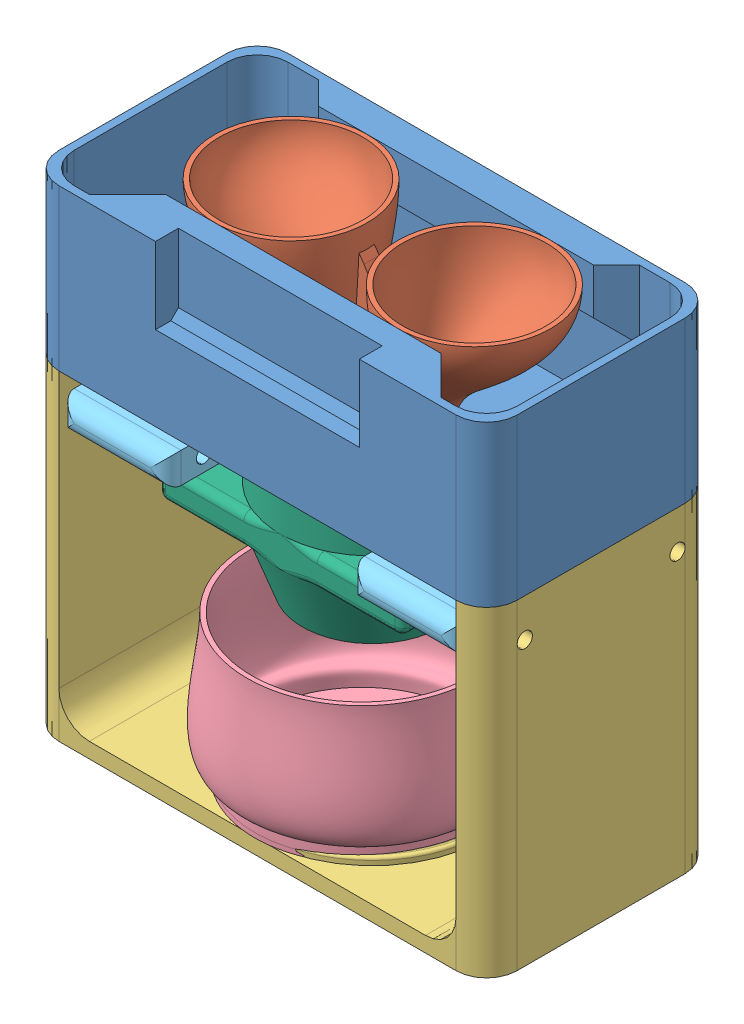
SolidWorks assembly sc_i_assembly, configuration Default. Lengths in mm.
Overall size (300 315.12 201.42).
6 component instances, 6 part files, 12 mates.
Components (placement in the parent):
- sc_i_body-1: sc_i_body [Default] at origin size (300 105 150)
- sc_i_bicontainer-2: sc_i_bicontainer [Default] at (92.0199 105 -80) x (-1 0 0) z (0 0 1) size (231.55 100.25 110.3)
- sc_i_base-1: sc_i_base [Default] at (0 -210 0) size (300 210 150)
- sc_i_pot-1: sc_i_pot [Default] at (148.9424 -197 -69.4018) size (200.61 98.32 201.42)
- sc_i_brewbase-1: sc_i_brewbase [Default] at (20 -35 0) size (260 20 150)
- sc_i_brewer-1: sc_i_brewer [Default] at (150 -35 -75) size (160 95 120)
Mates (geometry in assembly coordinates):
- Coincident7: coincident anti-aligned: plane of sc_i_body-1 through (0 5 0) normal (0 1 0); plane of sc_i_bicontainer-2 through (177.0199 5 -80) normal (0 -1 0)
- Coincident8: coincident anti-aligned: plane of sc_i_body-1 through (0 5 0) normal (0 1 0); plane of sc_i_bicontainer-2 through (127.0199 5 -80) normal (0 -1 0)
- Distance2: distance = 10 mm anti-aligned: plane of sc_i_bicontainer-2 through (-499907.9801 90 -85) normal (0 0 -1); plane of sc_i_body-1 through (0 15 -95) normal (0 0 1)
- Coincident10: coincident aligned: plane of sc_i_body-1 through (300 5 0) normal (1 0 0); plane of sc_i_base-1 through (300 -200 0) normal (1 0 0)
- Coincident11: coincident aligned: plane of sc_i_body-1 through (0 5 0) normal (0 0 1); plane of sc_i_base-1 through (0 -200 0) normal (0 0 1)
- Coincident12: coincident anti-aligned: plane of sc_i_body-1 through (0 0 0) normal (0 -1 0); plane of sc_i_base-1 through (0 0 0) normal (0 1 0)
- Coincident13: coincident anti-aligned: plane of sc_i_base-1 through (0 -200 0) normal (0 1 0); plane of sc_i_pot-1 through (148.9424 -200 -139.4018) normal (0 -1 0)
- Coincident14: coincident anti-aligned: plane of sc_i_base-1 through (280 0 0) normal (-1 0 0); plane of sc_i_brewbase-1 through (280 -15 0) normal (1 0 0)
- Parallel2: parallel anti-aligned: plane of sc_i_body-1 through (0 0 0) normal (0 -1 0); plane of sc_i_brewbase-1 through (20 -15 0) normal (0 1 0)
- Concentric4: concentric aligned: cylinder of sc_i_base-1 through (300 -25 -25) axis (-1 0 0) radius 5; cylinder of sc_i_brewbase-1 through (280 -25 -25) axis (-1 0 0) radius 5
- Concentric5: concentric anti-aligned: cylinder of sc_i_brewbase-1 through (150 -35 -75) axis (0 1 0) radius 60; cylinder of sc_i_brewer-1 through (150 -15 -75) axis (0 -1 0) radius 60
- Coincident16: coincident anti-aligned: plane of sc_i_brewbase-1 through (20 -35 0) normal (0 -1 0); plane of sc_i_brewer-1 through (150 -35 -75) normal (0 1 0)
